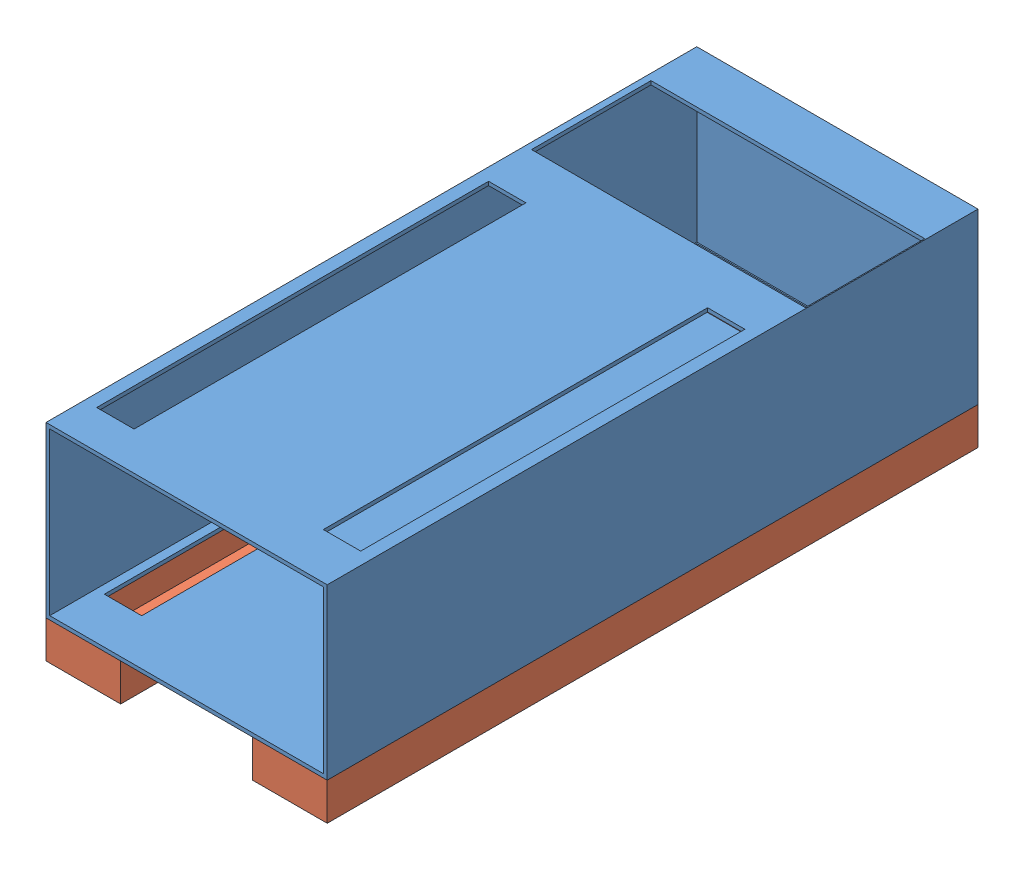
SolidWorks assembly Main_Box+Topextension, configuration Default. Lengths in mm.
Overall size (226 166 523).
3 component instances, 2 part files, 0 mates.
Components (placement in the parent):
- Main_Box+Topextension.STEP-1: Main_Box+Topextension.STEP [Default] at origin size (226 166 523)
  - Main_Box.STEP-1: Main_Box.STEP [Default] at origin size (226 136 523)
  - Topextension_Box.STEP-1: Topextension_Box.STEP [Default] at (55.7913 -68 58.8462) x (0 0 1) z (1 0 0) size (523 30 226)
